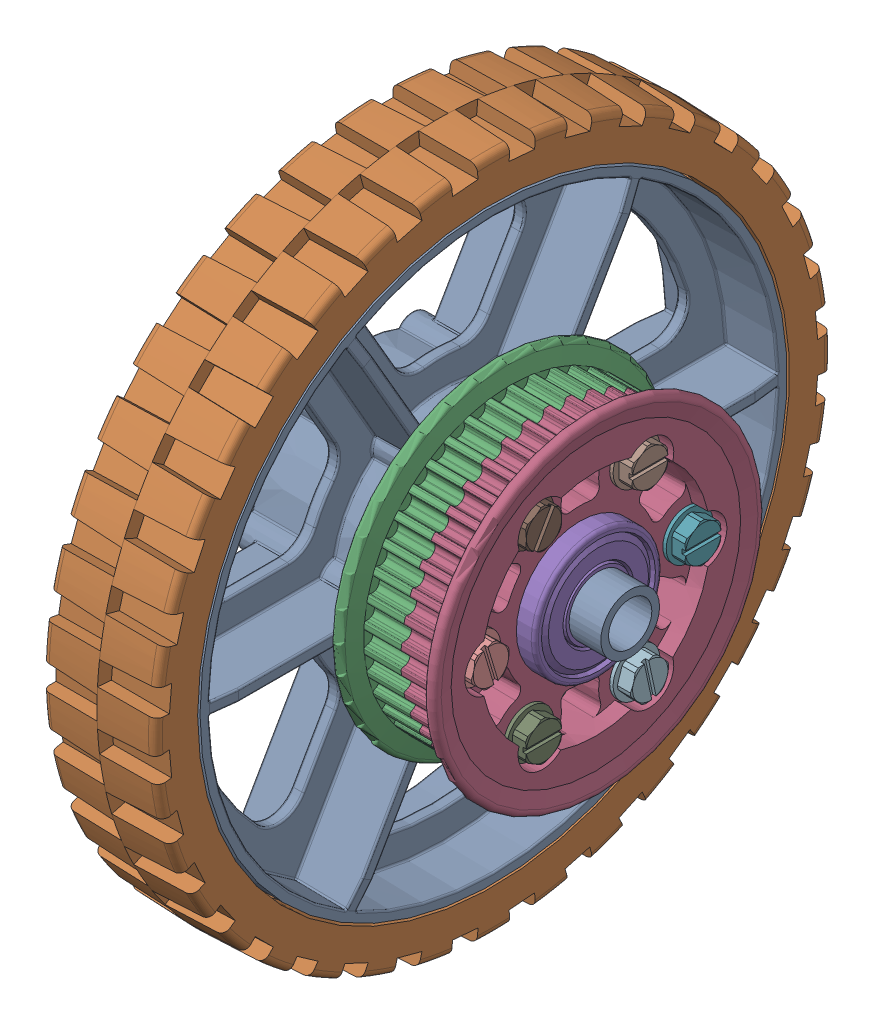
SolidWorks assembly 6 HiGrip with bearings, pulleys and spacers, configuration Default. Lengths in mm.
Overall size (85.56 152.4 152.4).
15 component instances, 7 part files, 0 mates.
Components (placement in the parent):
- 6 HiGrip Asm Rev II-1: 6 HiGrip Asm Rev II [Default] at (83.7987 67.439 110.9939) size (34.93 152.4 152.4)
  - 6 wheel Rev 4-1: 6 wheel Rev 4 [Default] at (-52.6446 9.4231 21.378) size (34.93 132.08 132.08)
  - 6 wheel tread II-1: 6 wheel tread II [Default] at (-65.3446 9.4231 21.378) x (0 0 -1) z (1 0 0) size (152.4 152.4 25.58)
- 42 tooth HTD Pulley half 2014-1: 42 tooth HTD Pulley half 2014 [Default] at (47.6006 76.862 132.3719) x (1 0 0) z (0 -0.5 0.866025) size (13 74.23 74.23)
- 42 tooth HTD Pulley half 2014-2: 42 tooth HTD Pulley half 2014 [Default] at (64.263 76.862 132.3719) x (-1 0 0) z (0 -0.499927 0.866067) size (13 74.23 74.23)
- 1614Z Bearing-1: 1614Z Bearing [Default] at (62.612 76.862 132.3719) x (0 -0.157148 -0.987575) z (-1 0 0) size (28.58 28.58 9.53)
- 1614Z Bearing-2: 1614Z Bearing [Default] at (15.2791 76.862 132.3719) x (0 0 -1) z (1 0 0) size (28.58 28.58 9.53)
- 10-24 Hex Washer Rolling x 1.25_93882A213-1: 10-24 Hex Washer Rolling x 1.25_93882A213 [Default] at (63.247 76.8605 108.5602) x (0 0 -1) z (1 0 0) size (10.52 10.52 35.59)
- 10-24 Hex Washer Rolling x 1.25_93882A213-2: 10-24 Hex Washer Rolling x 1.25_93882A213 [Default] at (63.247 97.4833 120.4656) x (0 0 -1) z (1 0 0) size (10.52 10.52 35.59)
- 10-24 Hex Washer Rolling x 1.25_93882A213-3: 10-24 Hex Washer Rolling x 1.25_93882A213 [Default] at (63.247 56.2398 144.2799) x (0 0 -1) z (1 0 0) size (10.52 10.52 35.59)
- 10-24 Hex Washer Rolling x 1.25_93882A213-4: 10-24 Hex Washer Rolling x 1.25_93882A213 [Default] at (63.247 76.8625 156.1852) x (0 -0.95788 -0.287168) z (1 0 0) size (10.52 10.52 35.59)
- 10-24 Hex Washer Rolling x 1.25_93882A213-5: 10-24 Hex Washer Rolling x 1.25_93882A213 [Default] at (63.247 97.4843 144.2781) x (0 -0.868976 0.494854) z (1 0 0) size (10.52 10.52 35.59)
- 10-24 Hex Washer Rolling x 1.25_93882A213-6: 10-24 Hex Washer Rolling x 1.25_93882A213 [Default] at (63.247 56.2388 120.4674) x (0 -0.977348 -0.211637) z (1 0 0) size (10.52 10.52 35.59)
- am-1306 spacer 0280 WashersUSA 13RS052001-1: am-1306 spacer 0280 WashersUSA 13RS052001 [Default] at (74.4865 76.862 132.3719) x (0 -0.35357 0.935408) z (-1 0 0) size (13.16 13.16 7.11)
- am-1307 spacer 0850 WashersUSA 13RS075054-1: am-1307 spacer 0850 WashersUSA 13RS075054 [Default] at (-11.0734 76.862 132.3719) x (0 0 -1) z (1 0 0) size (19.05 19.05 21.59)
